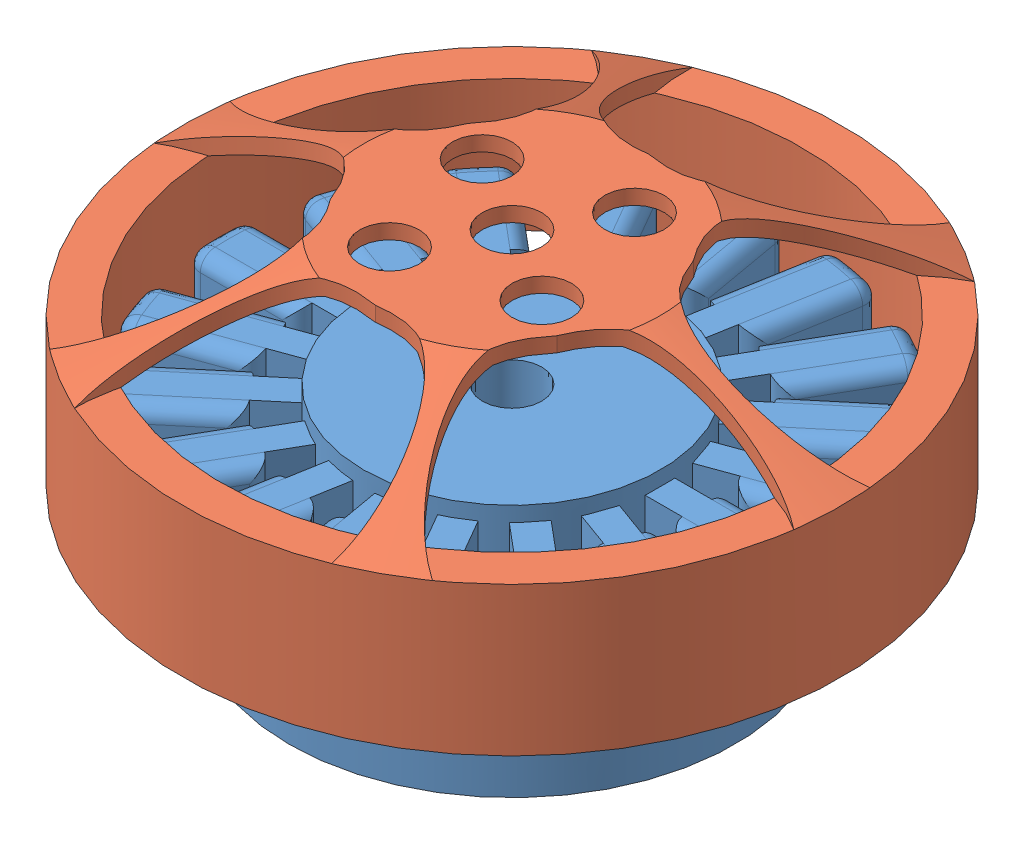
SolidWorks assembly T-motor 4004 kv300, configuration Default. Lengths in mm.
Overall size (60.94 23.74 60.94).
2 component instances, 2 part files, 2 mates.
Components (placement in the parent):
- motor rotor-1: motor rotor [Default] at (14.1676 19.6303 32.4608) size (40 13.5 39.72)
- motor stator-1: motor stator [Default] at (14.1676 19.6303 32.4608) x (0.854442 0 0.519546) z (0 1 0) size (44.35 44.35 16.24)
Mates (geometry in assembly coordinates):
- Concentric1: concentric anti-aligned: cylinder of motor rotor-1 through (14.1676 12.1303 32.4608) axis (0 1 0) radius 15; cylinder of motor stator-1 through (14.1676 29.6303 32.4608) axis (0 -1 0) radius 21.175
- Coincident1: coincident aligned: plane of motor rotor-1 through (14.1676 19.6303 32.4608) normal (0 -1 0); plane of motor stator-1 through (14.1676 19.6303 32.4608) normal (0 -1 0)
